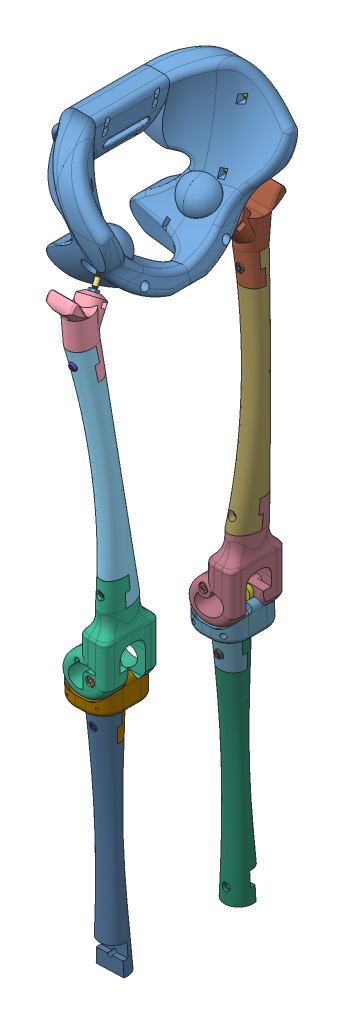
SolidWorks assembly 10_AH_001, configuration Default. Lengths in mm.
Overall size (197.88 962.11 294.61).
76 component instances, 21 part files, 131 mates.
Components (placement in the parent):
- 09_BA_001-1: 09_BA_001 [Default] at origin size (197.88 962.11 294.61) (flexible)
  - 02_01_PE_001-1: 02_01_PE_001 [Default] at origin size (197.88 220.17 282.18)
  - 6630T310_METRIC BLACK POLYPROPYLENE BALL KNOB-1: 6630T310_METRIC BLACK POLYPROPYLENE BALL KNOB [6630T31] at (-58.671 -58.8069 72.4936) x (0.804974 0.48308 0.344458) z (-0.194905 0.763657 -0.6155) size (38 38 37.9)
  - 92997A108_CORROSION-RESISTANT SETUP STUD-1: 92997A108_CORROSION-RESISTANT SETUP STUD [92997A108] at (-55.0653 -72.9345 83.8804) x (0.017759 0.630179 0.776247) z (0.194905 -0.763657 0.6155) size (6.34 6.15 50.8)
  - 03_02_FH_R_001-1: 03_02_FH_R_001 [Default] at (-45.3395 -121.5667 106.123) x (1 0 0) z (0 -0.087156 0.996195) size (46.92 105.86 63.35)
  - 03_01_FB_R_001-1: 03_01_FB_R_001 [Default] at (-44.1058 -425.8587 87.0078) x (1 0 0) z (0 -0.087156 0.996195) size (54.81 304.92 50.87)
  - 04_01_KT_R_001-1: 04_01_KT_R_001 [Default] at (-35.6321 -504.5163 84.7583) size (77.01 157.24 74.14)
  - 04_05_BL_001-1: 04_05_BL_001 [Default] at (-42.5577 -521.5571 84.8583) x (0.712112 0.702066 0) z (0 0 1) size (62.75 16 5.9)
  - 04_06_FL_001-1: 04_06_FL_001 [Default] at (-31.6099 -512.6089 78.7583) x (0.469804 -0.882771 0) z (0 0 1) size (67.43 16 5.9)
  - 04_02_KB_R_001-1: 04_02_KB_R_001 [Default] at (-43.0474 -546.2764 84.7583) x (0.999391 0.034899 0) z (0 0 1) size (78.49 85.12 75.75)
  - 05_01_TI_R_001-1: 05_01_TI_R_001 [Default] at (-42.6984 -556.2703 84.7583) x (0.999391 0.034899 0) z (0 0 1) size (38.19 304.9 38.19)
  - 6630T310_METRIC BLACK POLYPROPYLENE BALL KNOB-2: 6630T310_METRIC BLACK POLYPROPYLENE BALL KNOB [6630T31] at (-58.671 -58.8069 -72.4936) x (0.963134 0.030376 0.2673) z (-0.194905 0.763657 0.6155) size (38 38 37.9)
  - 92997A108_CORROSION-RESISTANT SETUP STUD-2: 92997A108_CORROSION-RESISTANT SETUP STUD [92997A108] at (-55.0653 -72.9345 -83.8804) x (-0.54916 -0.604916 0.576628) z (-0.194905 0.763657 0.6155) size (6.34 6.15 50.8)
  - 03_04_FH_L_001-1: 03_04_FH_L_001 [Default] at (-45.3395 -121.5667 -106.123) x (1 0 0) z (0 0.087156 0.996195) size (46.92 105.86 63.35)
  - 03_03_FB_L_001-1: 03_03_FB_L_001 [Default] at (-44.1058 -425.8587 -87.0078) x (1 0 0) z (0 0.087156 0.996195) size (54.81 304.92 50.87)
  - 04_03_KT_L_001-1: 04_03_KT_L_001 [Default] at (-35.6321 -504.5163 -84.7583) size (77.01 157.24 74.14)
  - 04_05_BL_001-2: 04_05_BL_001 [Default] at (-42.5577 -521.5571 -90.7583) x (0.712112 0.702066 0) z (0 0 1) size (62.75 16 5.9)
  - 04_06_FL_001-2: 04_06_FL_001 [Default] at (-31.6099 -512.6089 -84.6583) x (-0.469804 0.882771 0) z (0 0 1) size (67.43 16 5.9)
  - 04_04_KB_L_001-1: 04_04_KB_L_001 [Default] at (-43.0474 -546.2764 -84.8583) x (0.999391 0.034899 0) z (0 0 1) size (78.49 85.12 75.75)
  - 05_02_TI_001-1: 05_02_TI_001 [Default] at (-42.6984 -556.2703 -84.8583) x (0.999391 0.034899 0) z (0 0 1) size (38.19 304.9 38.19)
- 94645A205_HIGH-STRENGTH STEEL NYLON-INSERT LOCKNUT-1: 94645A205_HIGH-STRENGTH STEEL NYLON-INSERT LOCKNUT [94645A205] at (-47.544 52.8275 110.8479) x (0 -1 0) z (0 0 1) size (10 6.41 11.55)
- 94645A205_HIGH-STRENGTH STEEL NYLON-INSERT LOCKNUT-2: 94645A205_HIGH-STRENGTH STEEL NYLON-INSERT LOCKNUT [94645A205] at (-47.544 -21.0136 84.8541) x (0 -1 0) z (0 0 1) size (10 6.41 11.55)
- 94645A205_HIGH-STRENGTH STEEL NYLON-INSERT LOCKNUT-4: 94645A205_HIGH-STRENGTH STEEL NYLON-INSERT LOCKNUT [94645A205] at (-74.544 -75.4386 54.7323) x (0 1 0) z (0 0 1) size (10 6.41 11.55)
- 94645A205_HIGH-STRENGTH STEEL NYLON-INSERT LOCKNUT-6: 94645A205_HIGH-STRENGTH STEEL NYLON-INSERT LOCKNUT [94645A205] at (-47.544 52.8275 -110.8479) x (0 1 0) z (0 0 -1) size (10 6.41 11.55)
- 94645A205_HIGH-STRENGTH STEEL NYLON-INSERT LOCKNUT-8: 94645A205_HIGH-STRENGTH STEEL NYLON-INSERT LOCKNUT [94645A205] at (-47.544 -21.0136 -84.8541) x (0 1 0) z (0 0 -1) size (10 6.41 11.55)
- 94645A205_HIGH-STRENGTH STEEL NYLON-INSERT LOCKNUT-10: 94645A205_HIGH-STRENGTH STEEL NYLON-INSERT LOCKNUT [94645A205] at (-74.544 -75.4386 -54.7323) x (0 1 0) z (0 0 1) size (10 6.41 11.55)
- 94645A205_HIGH-STRENGTH STEEL NYLON-INSERT LOCKNUT-12: 94645A205_HIGH-STRENGTH STEEL NYLON-INSERT LOCKNUT [94645A205] at (-104.3146 69.6752 36.5) x (0 1 0) z (-1 0 0) size (10 6.41 11.55)
- 94645A205_HIGH-STRENGTH STEEL NYLON-INSERT LOCKNUT-14: 94645A205_HIGH-STRENGTH STEEL NYLON-INSERT LOCKNUT [94645A205] at (-121.884 56.6312 36.5) x (0 1 0) z (-1 0 0) size (10 6.41 11.55)
- 94645A205_HIGH-STRENGTH STEEL NYLON-INSERT LOCKNUT-16: 94645A205_HIGH-STRENGTH STEEL NYLON-INSERT LOCKNUT [94645A205] at (-121.884 56.6312 -30.5) x (0 1 0) z (-1 0 0) size (10 6.41 11.55)
- 94645A205_HIGH-STRENGTH STEEL NYLON-INSERT LOCKNUT-18: 94645A205_HIGH-STRENGTH STEEL NYLON-INSERT LOCKNUT [94645A205] at (-104.3146 69.6752 -30.5) x (0 1 0) z (-1 0 0) size (10 6.41 11.55)
- 94645A205_HIGH-STRENGTH STEEL NYLON-INSERT LOCKNUT-20: 94645A205_HIGH-STRENGTH STEEL NYLON-INSERT LOCKNUT [94645A205] at (-51.8494 -85.5349 94.0361) x (0.194905 0.645175 0.738757) z (0.961262 0.024023 -0.274588) size (10 6.41 11.55)
- 94645A205_HIGH-STRENGTH STEEL NYLON-INSERT LOCKNUT-22: 94645A205_HIGH-STRENGTH STEEL NYLON-INSERT LOCKNUT [94645A205] at (-51.8494 -85.5349 -94.0361) x (0.194905 0.645175 -0.738757) z (-0.961262 -0.024023 -0.274588) size (10 6.41 11.55)
- 94645A205_HIGH-STRENGTH STEEL NYLON-INSERT LOCKNUT-24: 94645A205_HIGH-STRENGTH STEEL NYLON-INSERT LOCKNUT [94645A205] at (-30.2115 -92.3012 -13.5) x (0.866025 -0.5 0) z (0.5 0.866025 0) size (10 6.41 11.55)
- 94645A205_HIGH-STRENGTH STEEL NYLON-INSERT LOCKNUT-26: 94645A205_HIGH-STRENGTH STEEL NYLON-INSERT LOCKNUT [94645A205] at (-41.8015 -140.2036 100.5688) x (0.866025 -0.498097 -0.043578) z (0.5 0.86273 0.075479) size (10 6.41 11.55)
- 94645A205_HIGH-STRENGTH STEEL NYLON-INSERT LOCKNUT-28: 94645A205_HIGH-STRENGTH STEEL NYLON-INSERT LOCKNUT [94645A205] at (-41.8015 -140.2036 -100.5688) x (0.866025 -0.498097 0.043578) z (-0.5 -0.86273 0.075479) size (10 6.41 11.55)
- 94645A205_HIGH-STRENGTH STEEL NYLON-INSERT LOCKNUT-30: 94645A205_HIGH-STRENGTH STEEL NYLON-INSERT LOCKNUT [94645A205] at (-23.6321 -408.0461 -101.9838) x (1 0 0) z (0 0.996195 -0.087156) size (10 6.41 11.55)
- 94645A205_HIGH-STRENGTH STEEL NYLON-INSERT LOCKNUT-36: 94645A205_HIGH-STRENGTH STEEL NYLON-INSERT LOCKNUT [94645A205] at (-41.8513 -575.3023 71.7583) x (0.999391 0.034899 0) z (-0.034899 0.999391 0) size (10 6.41 11.55)
- 94645A205_HIGH-STRENGTH STEEL NYLON-INSERT LOCKNUT-39: 94645A205_HIGH-STRENGTH STEEL NYLON-INSERT LOCKNUT [94645A205] at (-23.6321 -408.0461 101.9838) x (-0.5 0.86273 0.075479) z (0.866025 0.498097 0.043578) size (10 6.41 11.55)
- 94645A205_HIGH-STRENGTH STEEL NYLON-INSERT LOCKNUT-41: 94645A205_HIGH-STRENGTH STEEL NYLON-INSERT LOCKNUT [94645A205] at (-41.8513 -575.3023 -71.8583) x (0.999391 0.034899 0) z (0.034899 -0.999391 0) size (10 6.41 11.55)
- 91239A330_CLASS 10.9 STL BUTTON-HEAD SOCKET CAP SCREW-1: 91239A330_CLASS 10.9 STL BUTTON-HEAD SOCKET CAP SCREW [91239A330] at (-121.884 56.6312 66.8) size (10.5 10.5 38.95)
- 91239A330_CLASS 10.9 STL BUTTON-HEAD SOCKET CAP SCREW-2: 91239A330_CLASS 10.9 STL BUTTON-HEAD SOCKET CAP SCREW [91239A330] at (-77.844 52.8275 110.8479) x (0 0 1) z (-1 0 0) size (10.5 10.5 38.95)
- 91239A330_CLASS 10.9 STL BUTTON-HEAD SOCKET CAP SCREW-4: 91239A330_CLASS 10.9 STL BUTTON-HEAD SOCKET CAP SCREW [91239A330] at (-104.3146 69.6752 66.8) x (0.959125 0.282984 0) z (0 0 1) size (10.5 10.5 38.95)
- 91239A330_CLASS 10.9 STL BUTTON-HEAD SOCKET CAP SCREW-6: 91239A330_CLASS 10.9 STL BUTTON-HEAD SOCKET CAP SCREW [91239A330] at (-104.3146 69.6752 -66.8) x (-0.5 0.866025 0) z (0 0 -1) size (10.5 10.5 38.95)
- 91239A330_CLASS 10.9 STL BUTTON-HEAD SOCKET CAP SCREW-8: 91239A330_CLASS 10.9 STL BUTTON-HEAD SOCKET CAP SCREW [91239A330] at (-121.884 56.6312 -66.8) x (-0.642788 0.766044 0) z (0 0 -1) size (10.5 10.5 38.95)
- 91239A330_CLASS 10.9 STL BUTTON-HEAD SOCKET CAP SCREW-10: 91239A330_CLASS 10.9 STL BUTTON-HEAD SOCKET CAP SCREW [91239A330] at (-77.844 52.8275 -110.8479) x (0 0 1) z (-1 0 0) size (10.5 10.5 38.95)
- 91239A330_CLASS 10.9 STL BUTTON-HEAD SOCKET CAP SCREW-12: 91239A330_CLASS 10.9 STL BUTTON-HEAD SOCKET CAP SCREW [91239A330] at (-77.844 -21.0136 -84.8541) x (0 0 1) z (-1 0 0) size (10.5 10.5 38.95)
- 91239A330_CLASS 10.9 STL BUTTON-HEAD SOCKET CAP SCREW-14: 91239A330_CLASS 10.9 STL BUTTON-HEAD SOCKET CAP SCREW [91239A330] at (-77.844 -21.0136 84.8541) x (0 0 1) z (-1 0 0) size (10.5 10.5 38.95)
- 91239A330_CLASS 10.9 STL BUTTON-HEAD SOCKET CAP SCREW-16: 91239A330_CLASS 10.9 STL BUTTON-HEAD SOCKET CAP SCREW [91239A330] at (-44.244 -75.4386 -54.7323) x (0 0.171049 -0.985262) z (1 0 0) size (10.5 10.5 38.95)
- 91239A330_CLASS 10.9 STL BUTTON-HEAD SOCKET CAP SCREW-18: 91239A330_CLASS 10.9 STL BUTTON-HEAD SOCKET CAP SCREW [91239A330] at (-44.244 -75.4386 54.7323) x (0 0 -1) z (1 0 0) size (10.5 10.5 38.95)
- 91239A330_CLASS 10.9 STL BUTTON-HEAD SOCKET CAP SCREW-20: 91239A330_CLASS 10.9 STL BUTTON-HEAD SOCKET CAP SCREW [91239A330] at (-30.2115 -92.3012 16.8) x (0.985697 -0.168526 0) z (0 0 1) size (10.5 10.5 38.95)
- 91239A330_CLASS 10.9 STL BUTTON-HEAD SOCKET CAP SCREW-22: 91239A330_CLASS 10.9 STL BUTTON-HEAD SOCKET CAP SCREW [91239A330] at (-41.8015 -142.9042 131.4369) x (0.92579 -0.376599 -0.032948) z (0 -0.087156 0.996195) size (10.5 10.5 38.95)
- 91239A330_CLASS 10.9 STL BUTTON-HEAD SOCKET CAP SCREW-24: 91239A330_CLASS 10.9 STL BUTTON-HEAD SOCKET CAP SCREW [91239A330] at (-41.8015 -142.9042 -131.4369) x (-0.916799 -0.39783 0.034806) z (0 -0.087156 -0.996195) size (10.5 10.5 38.95)
- 91239A330_CLASS 10.9 STL BUTTON-HEAD SOCKET CAP SCREW-26: 91239A330_CLASS 10.9 STL BUTTON-HEAD SOCKET CAP SCREW [91239A330] at (-23.6321 -405.415 -71.9097) x (0.92535 -0.377672 0.033042) z (0 0.087156 0.996195) size (10.5 10.5 38.95)
- 91239A330_CLASS 10.9 STL BUTTON-HEAD SOCKET CAP SCREW-28: 91239A330_CLASS 10.9 STL BUTTON-HEAD SOCKET CAP SCREW [91239A330] at (-23.6321 -405.415 71.9097) x (-0.509415 -0.857247 -0.074999) z (0 0.087156 -0.996195) size (10.5 10.5 38.95)
- 91239A330_CLASS 10.9 STL BUTTON-HEAD SOCKET CAP SCREW-30: 91239A330_CLASS 10.9 STL BUTTON-HEAD SOCKET CAP SCREW [91239A330] at (-41.8513 -575.3023 -102.1583) x (-0.5 -0.866025 0) z (0 0 -1) size (10.5 10.5 38.95)
- 91239A330_CLASS 10.9 STL BUTTON-HEAD SOCKET CAP SCREW-32: 91239A330_CLASS 10.9 STL BUTTON-HEAD SOCKET CAP SCREW [91239A330] at (-41.8513 -575.3023 102.0583) x (-0.675882 0.73701 0) z (0 0 1) size (10.5 10.5 38.95)
- 91595A476_METRIC ALLOY STEEL DOWEL PIN-1: 91595A476_METRIC ALLOY STEEL DOWEL PIN [91595A476] at (-59.6817 24.9417 100.1676) x (1 0 0) z (0 0.020434 0.999791) size (40 6 6)
- 91595A476_METRIC ALLOY STEEL DOWEL PIN-2: 91595A476_METRIC ALLOY STEEL DOWEL PIN [91595A476] at (-59.6817 -3.0834 90.0569) x (1 0 0) z (0 -0.138344 0.990384) size (40 6 6)
- 91595A476_METRIC ALLOY STEEL DOWEL PIN-4: 91595A476_METRIC ALLOY STEEL DOWEL PIN [91595A476] at (-59.6817 -93.1682 40.0283) x (1 0 0) z (0 -0.263326 0.964707) size (40 6 6)
- 91595A476_METRIC ALLOY STEEL DOWEL PIN-6: 91595A476_METRIC ALLOY STEEL DOWEL PIN [91595A476] at (-59.6817 -93.1682 -40.0283) x (1 0 0) z (0 -0.780184 0.62555) size (40 6 6)
- 91595A476_METRIC ALLOY STEEL DOWEL PIN-8: 91595A476_METRIC ALLOY STEEL DOWEL PIN [91595A476] at (-62.6563 -3.0834 -90.0569) x (-1 0 0) z (0 0.779019 -0.627) size (40 6 6)
- 91595A476_METRIC ALLOY STEEL DOWEL PIN-10: 91595A476_METRIC ALLOY STEEL DOWEL PIN [91595A476] at (-59.6817 24.9417 -100.1676) x (1 0 0) z (0 -0.947084 0.320986) size (40 6 6)
- 90695A038_CLASS 04 STEEL THIN HEX NUT - DIN 439B-1: 90695A038_CLASS 04 STEEL THIN HEX NUT - DIN 439B [90695A038] at (-53.3306 -79.7311 89.3583) x (0.978461 0.194905 -0.06802) z (-0.06802 0.6155 0.785196) size (10 3.98 11.55)
- 90695A038_CLASS 04 STEEL THIN HEX NUT - DIN 439B-2: 90695A038_CLASS 04 STEEL THIN HEX NUT - DIN 439B [90695A038] at (-53.3306 -79.7311 -89.3583) x (0.826706 -0.20978 0.522062) z (-0.527796 -0.61059 0.590433) size (10 3.98 11.55)
- 94510A255_BRASS SCREW-TO-EXPAND INSERTS-1: 94510A255_BRASS SCREW-TO-EXPAND INSERTS [94510A255] at (-25.9121 -505.1463 120.7537) x (1 0 0) z (0 -1 0) size (9.53 13.25 9.53)
- 94510A255_BRASS SCREW-TO-EXPAND INSERTS-2: 94510A255_BRASS SCREW-TO-EXPAND INSERTS [94510A255] at (-25.9121 -505.1463 -120.7537) x (0.972777 0.231744 0) z (-0.231744 0.972777 0) size (9.53 13.25 9.53)
- 94510A255_BRASS SCREW-TO-EXPAND INSERTS-4: 94510A255_BRASS SCREW-TO-EXPAND INSERTS [94510A255] at (-43.6921 -489.9063 48.7629) x (-0.34202 0.939693 0) z (-0.939693 -0.34202 0) size (9.53 13.25 9.53)
- 94510A255_BRASS SCREW-TO-EXPAND INSERTS-6: 94510A255_BRASS SCREW-TO-EXPAND INSERTS [94510A255] at (-43.6921 -489.9063 -48.7629) x (-0.130134 -0.991496 0) z (-0.991496 0.130134 0) size (9.53 13.25 9.53)
- 97493A126_ METRIC PARTIALLY THREADED STUDS-1: 97493A126_ METRIC PARTIALLY THREADED STUDS [97493A126] at (-25.9121 -505.1463 -107.6583) x (-0.1 0.994987 0) z (0 0 1) size (6.22 6.14 30.07)
- 97493A126_ METRIC PARTIALLY THREADED STUDS-2: 97493A126_ METRIC PARTIALLY THREADED STUDS [97493A126] at (-43.6921 -489.9063 -61.8583) x (0.997236 0.074297 0) z (0 0 -1) size (6.22 6.14 30.07)
- 97493A126_ METRIC PARTIALLY THREADED STUDS-4: 97493A126_ METRIC PARTIALLY THREADED STUDS [97493A126] at (-43.6921 -489.9063 61.8583) x (0.989622 0.143697 0) z (0 0 1) size (6.22 6.14 30.07)
- 97493A126_ METRIC PARTIALLY THREADED STUDS-6: 97493A126_ METRIC PARTIALLY THREADED STUDS [97493A126] at (-25.9121 -505.1463 107.6583) x (0.911684 0.410891 0) z (0 0 -1) size (6.22 6.14 30.07)
- 97493A126_ METRIC PARTIALLY THREADED STUDS-9: 97493A126_ METRIC PARTIALLY THREADED STUDS [97493A126] at (-19.5277 -535.3116 92.5583) x (-1 0 0) z (0 0 -1) size (6.22 6.14 30.07)
- 97493A126_ METRIC PARTIALLY THREADED STUDS-10: 97493A126_ METRIC PARTIALLY THREADED STUDS [97493A126] at (-59.2033 -537.9679 92.5583) x (-0.987351 -0.158553 0) z (0 0 -1) size (6.22 6.14 30.07)
- 97493A126_ METRIC PARTIALLY THREADED STUDS-12: 97493A126_ METRIC PARTIALLY THREADED STUDS [97493A126] at (-19.5277 -535.3116 -92.6583) x (-0.994367 -0.105992 0) z (0 0 1) size (6.22 6.14 30.07)
- 97493A126_ METRIC PARTIALLY THREADED STUDS-14: 97493A126_ METRIC PARTIALLY THREADED STUDS [97493A126] at (-59.2033 -537.9679 -92.6583) x (-0.999918 -0.012843 0) z (0 0 1) size (6.22 6.14 30.07)
Mates (geometry in assembly coordinates):
- Coincident1: coincident anti-aligned: plane of 09_BipedalRobot_Assembly-1/02_01_Pelvis-1 through (-47.544 0 0) normal (1 0 0); plane of 94645A205_HIGH-STRENGTH STEEL NYLON-INSERT LOCKNUT-1 through (-47.544 47.8275 107.9612) normal (-1 0 0)
- Parallel1: parallel anti-aligned: plane of 09_BipedalRobot_Assembly-1/02_01_Pelvis-1 through (-41.044 57.9775 107.8746) normal (0 -1 0); plane of 94645A205_HIGH-STRENGTH STEEL NYLON-INSERT LOCKNUT-1 through (-41.544 57.8275 107.9612) normal (0 1 0)
- Concentric4: concentric anti-aligned: circle of 09_BipedalRobot_Assembly-1/02_01_Pelvis-1; circle of 94645A205_HIGH-STRENGTH STEEL NYLON-INSERT LOCKNUT-1
- Coincident3: coincident anti-aligned: plane of 09_BipedalRobot_Assembly-1/02_01_Pelvis-1 through (-47.544 0 0) normal (1 0 0); plane of 94645A205_HIGH-STRENGTH STEEL NYLON-INSERT LOCKNUT-2 through (-47.544 -26.0136 81.9674) normal (-1 0 0)
- Parallel2: parallel anti-aligned: plane of 09_BipedalRobot_Assembly-1/02_01_Pelvis-1 through (-41.044 -15.8636 81.8808) normal (0 -1 0); plane of 94645A205_HIGH-STRENGTH STEEL NYLON-INSERT LOCKNUT-2 through (-41.544 -16.0136 81.9674) normal (0 1 0)
- Concentric5: concentric anti-aligned: circle of 09_BipedalRobot_Assembly-1/02_01_Pelvis-1; circle of 94645A205_HIGH-STRENGTH STEEL NYLON-INSERT LOCKNUT-2
- Parallel3: parallel anti-aligned: plane of 09_BipedalRobot_Assembly-1/02_01_Pelvis-1 through (-81.044 -80.5886 57.7056) normal (0 1 0); plane of 94645A205_HIGH-STRENGTH STEEL NYLON-INSERT LOCKNUT-4 through (-80.544 -80.4386 51.8455) normal (0 -1 0)
- Concentric6: concentric anti-aligned: circle of 09_BipedalRobot_Assembly-1/02_01_Pelvis-1; circle of 94645A205_HIGH-STRENGTH STEEL NYLON-INSERT LOCKNUT-4
- Coincident5: coincident anti-aligned: plane of 09_BipedalRobot_Assembly-1/02_01_Pelvis-1 through (-74.544 0 0) normal (-1 0 0); plane of 94645A205_HIGH-STRENGTH STEEL NYLON-INSERT LOCKNUT-4 through (-74.544 -70.4386 51.8455) normal (1 0 0)
- Coincident6: coincident anti-aligned: plane of 09_BipedalRobot_Assembly-1/02_01_Pelvis-1 through (-47.544 0 0) normal (1 0 0); plane of 94645A205_HIGH-STRENGTH STEEL NYLON-INSERT LOCKNUT-6 through (-47.544 57.8275 -107.9612) normal (-1 0 0)
- Parallel4: parallel anti-aligned: plane of 09_BipedalRobot_Assembly-1/02_01_Pelvis-1 through (-41.044 47.6775 -113.8213) normal (0 1 0); plane of 94645A205_HIGH-STRENGTH STEEL NYLON-INSERT LOCKNUT-6 through (-41.544 47.8275 -107.9612) normal (0 -1 0)
- Concentric7: concentric aligned: circle of 09_BipedalRobot_Assembly-1/02_01_Pelvis-1; circle of 94645A205_HIGH-STRENGTH STEEL NYLON-INSERT LOCKNUT-6
- Coincident7: coincident anti-aligned: plane of 09_BipedalRobot_Assembly-1/02_01_Pelvis-1 through (-47.544 0 0) normal (1 0 0); plane of 94645A205_HIGH-STRENGTH STEEL NYLON-INSERT LOCKNUT-8 through (-47.544 -16.0136 -81.9674) normal (-1 0 0)
- Parallel5: parallel anti-aligned: plane of 09_BipedalRobot_Assembly-1/02_01_Pelvis-1 through (-41.044 -26.1636 -87.8275) normal (0 1 0); plane of 94645A205_HIGH-STRENGTH STEEL NYLON-INSERT LOCKNUT-8 through (-41.544 -26.0136 -81.9674) normal (0 -1 0)
- Concentric8: concentric aligned: circle of 09_BipedalRobot_Assembly-1/02_01_Pelvis-1; circle of 94645A205_HIGH-STRENGTH STEEL NYLON-INSERT LOCKNUT-8
- Coincident8: coincident anti-aligned: plane of 09_BipedalRobot_Assembly-1/02_01_Pelvis-1 through (-74.544 0 0) normal (-1 0 0); plane of 94645A205_HIGH-STRENGTH STEEL NYLON-INSERT LOCKNUT-10 through (-74.544 -70.4386 -57.619) normal (1 0 0)
- Parallel6: parallel anti-aligned: plane of 09_BipedalRobot_Assembly-1/02_01_Pelvis-1 through (-81.044 -80.5886 -57.7056) normal (0 1 0); plane of 94645A205_HIGH-STRENGTH STEEL NYLON-INSERT LOCKNUT-10 through (-80.544 -80.4386 -57.619) normal (0 -1 0)
- Concentric11: concentric aligned: circle of 09_BipedalRobot_Assembly-1/02_01_Pelvis-1; circle of 94645A205_HIGH-STRENGTH STEEL NYLON-INSERT LOCKNUT-10
- Coincident9: coincident anti-aligned: plane of 09_BipedalRobot_Assembly-1/02_01_Pelvis-1 through (0 0 36.5) normal (0 0 -1); plane of 94645A205_HIGH-STRENGTH STEEL NYLON-INSERT LOCKNUT-12 through (-101.4278 74.6752 36.5) normal (0 0 1)
- Parallel7: parallel anti-aligned: plane of 09_BipedalRobot_Assembly-1/02_01_Pelvis-1 through (-101.3412 64.5252 30.5) normal (0 1 0); plane of 94645A205_HIGH-STRENGTH STEEL NYLON-INSERT LOCKNUT-12 through (-101.4278 64.6752 30.5) normal (0 -1 0)
- Concentric12: concentric anti-aligned: circle of 09_BipedalRobot_Assembly-1/02_01_Pelvis-1; circle of 94645A205_HIGH-STRENGTH STEEL NYLON-INSERT LOCKNUT-12
- Coincident10: coincident anti-aligned: plane of 09_BipedalRobot_Assembly-1/02_01_Pelvis-1 through (0 0 36.5) normal (0 0 -1); plane of 94645A205_HIGH-STRENGTH STEEL NYLON-INSERT LOCKNUT-14 through (-118.9973 61.6312 36.5) normal (0 0 1)
- Parallel8: parallel anti-aligned: plane of 09_BipedalRobot_Assembly-1/02_01_Pelvis-1 through (-118.9107 51.4812 30.5) normal (0 1 0); plane of 94645A205_HIGH-STRENGTH STEEL NYLON-INSERT LOCKNUT-14 through (-118.9973 51.6312 30.5) normal (0 -1 0)
- Concentric13: concentric anti-aligned: circle of 09_BipedalRobot_Assembly-1/02_01_Pelvis-1; circle of 94645A205_HIGH-STRENGTH STEEL NYLON-INSERT LOCKNUT-14
- Coincident11: coincident anti-aligned: plane of 09_BipedalRobot_Assembly-1/02_01_Pelvis-1 through (0 0 -30.5) normal (0 0 -1); plane of 94645A205_HIGH-STRENGTH STEEL NYLON-INSERT LOCKNUT-16 through (-118.9973 61.6312 -30.5) normal (0 0 1)
- Parallel9: parallel anti-aligned: plane of 09_BipedalRobot_Assembly-1/02_01_Pelvis-1 through (-118.9107 51.4812 -30.5) normal (0 1 0); plane of 94645A205_HIGH-STRENGTH STEEL NYLON-INSERT LOCKNUT-16 through (-118.9973 51.6312 -36.5) normal (0 -1 0)
- Concentric14: concentric anti-aligned: circle of 09_BipedalRobot_Assembly-1/02_01_Pelvis-1; circle of 94645A205_HIGH-STRENGTH STEEL NYLON-INSERT LOCKNUT-16
- Coincident12: coincident anti-aligned: plane of 09_BipedalRobot_Assembly-1/02_01_Pelvis-1 through (0 0 -30.5) normal (0 0 -1); plane of 94645A205_HIGH-STRENGTH STEEL NYLON-INSERT LOCKNUT-18 through (-101.4278 74.6752 -30.5) normal (0 0 1)
- Parallel10: parallel anti-aligned: plane of 09_BipedalRobot_Assembly-1/02_01_Pelvis-1 through (-101.3412 64.5252 -30.5) normal (0 1 0); plane of 94645A205_HIGH-STRENGTH STEEL NYLON-INSERT LOCKNUT-18 through (-101.4278 64.6752 -36.5) normal (0 -1 0)
- Concentric15: concentric anti-aligned: circle of 09_BipedalRobot_Assembly-1/02_01_Pelvis-1; circle of 94645A205_HIGH-STRENGTH STEEL NYLON-INSERT LOCKNUT-18
- Coincident13: coincident anti-aligned: plane of 09_BipedalRobot_Assembly-1/03_02_FemurHead_Right-1 through (-53.3962 -90.6553 88.173) normal (0.194905 -0.763657 0.6155); plane of 94645A205_HIGH-STRENGTH STEEL NYLON-INSERT LOCKNUT-20 through (-53.6498 -82.3783 98.5226) normal (-0.194905 0.763657 -0.6155)
- Parallel11: parallel anti-aligned: plane of 09_BipedalRobot_Assembly-1/03_02_FemurHead_Right-1 through (-19.7212 -93.0069 85.1522) normal (0.194905 0.645175 0.738757); plane of 94645A205_HIGH-STRENGTH STEEL NYLON-INSERT LOCKNUT-20 through (-54.4294 -93.412 94.828) normal (-0.194905 -0.645175 -0.738757)
- Concentric16: concentric aligned: circle of 09_BipedalRobot_Assembly-1/03_02_FemurHead_Right-1; circle of 94645A205_HIGH-STRENGTH STEEL NYLON-INSERT LOCKNUT-20
- Coincident14: coincident anti-aligned: plane of 09_BipedalRobot_Assembly-1/03_04_FemurHead_Left-1 through (-53.3962 -90.6553 -88.173) normal (0.194905 -0.763657 -0.6155); plane of 94645A205_HIGH-STRENGTH STEEL NYLON-INSERT LOCKNUT-22 through (-48.0999 -82.2396 -96.9372) normal (-0.194905 0.763657 0.6155)
- Parallel12: parallel anti-aligned: plane of 09_BipedalRobot_Assembly-1/03_04_FemurHead_Left-1 through (-19.7212 -93.0069 -85.1522) normal (0.194905 0.645175 -0.738757); plane of 94645A205_HIGH-STRENGTH STEEL NYLON-INSERT LOCKNUT-22 through (-48.8795 -93.2733 -93.2427) normal (-0.194905 -0.645175 0.738757)
- Concentric17: concentric anti-aligned: circle of 09_BipedalRobot_Assembly-1/03_04_FemurHead_Left-1; circle of 94645A205_HIGH-STRENGTH STEEL NYLON-INSERT LOCKNUT-22
- Coincident15: coincident anti-aligned: plane of 09_BipedalRobot_Assembly-1/02_01_Pelvis-1 through (0 0 -13.5) normal (0 0 -1); plane of 94645A205_HIGH-STRENGTH STEEL NYLON-INSERT LOCKNUT-24 through (-27.3247 -97.3012 -13.5) normal (0 0 1)
- Parallel13: parallel anti-aligned: plane of 09_BipedalRobot_Assembly-1/02_01_Pelvis-1 through (-36.1582 -92.3012 -143.5354) normal (0.866025 -0.5 0); plane of 94645A205_HIGH-STRENGTH STEEL NYLON-INSERT LOCKNUT-24 through (-35.985 -92.3012 -19.5) normal (-0.866025 0.5 0)
- Concentric18: concentric aligned: circle of 09_BipedalRobot_Assembly-1/02_01_Pelvis-1; circle of 94645A205_HIGH-STRENGTH STEEL NYLON-INSERT LOCKNUT-24
- Coincident16: coincident anti-aligned: plane of 09_BipedalRobot_Assembly-1/03_02_FemurHead_Right-1 through (-45.3395 -121.2261 102.2291) normal (0 0.087156 -0.996195); plane of 94645A205_HIGH-STRENGTH STEEL NYLON-INSERT LOCKNUT-26 through (-38.9147 -145.1846 100.133) normal (0 -0.087156 0.996195)
- Parallel14: parallel anti-aligned: plane of 09_BipedalRobot_Assembly-1/03_02_FemurHead_Right-1 through (-47.8637 -139.5343 92.9194) normal (0.866025 -0.498097 -0.043578); plane of 94645A205_HIGH-STRENGTH STEEL NYLON-INSERT LOCKNUT-26 through (-47.575 -139.6806 94.5917) normal (-0.866025 0.498097 0.043578)
- Concentric19: concentric aligned: circle of 09_BipedalRobot_Assembly-1/03_02_FemurHead_Right-1; circle of 94645A205_HIGH-STRENGTH STEEL NYLON-INSERT LOCKNUT-26
- Coincident17: coincident anti-aligned: plane of 09_BipedalRobot_Assembly-1/03_04_FemurHead_Left-1 through (-45.3395 -121.2261 -102.2291) normal (0 0.087156 0.996195); plane of 94645A205_HIGH-STRENGTH STEEL NYLON-INSERT LOCKNUT-28 through (-36.028 -140.2036 -100.5688) normal (0 -0.087156 -0.996195)
- Parallel15: parallel anti-aligned: plane of 09_BipedalRobot_Assembly-1/03_04_FemurHead_Left-1 through (-47.8637 -139.5343 -92.9194) normal (0.866025 -0.498097 0.043578); plane of 94645A205_HIGH-STRENGTH STEEL NYLON-INSERT LOCKNUT-28 through (-44.6882 -134.6997 -95.0274) normal (-0.866025 0.498097 -0.043578)
- Concentric20: concentric anti-aligned: circle of 09_BipedalRobot_Assembly-1/03_04_FemurHead_Left-1; circle of 94645A205_HIGH-STRENGTH STEEL NYLON-INSERT LOCKNUT-28
- Coincident18: coincident anti-aligned: plane of 09_BipedalRobot_Assembly-1/04_03_KneeTop_Left-1 through (-35.6321 -505.2791 -93.4771) normal (0 -0.087156 -0.996195); plane of 94645A205_HIGH-STRENGTH STEEL NYLON-INSERT LOCKNUT-30 through (-18.6321 -410.9219 -101.7322) normal (0 0.087156 0.996195)
- Parallel16: parallel anti-aligned: plane of 09_BipedalRobot_Assembly-1/04_03_KneeTop_Left-1 through (-28.8821 -407.1183 -126.1567) normal (1 0 0); plane of 94645A205_HIGH-STRENGTH STEEL NYLON-INSERT LOCKNUT-30 through (-28.6321 -411.4448 -107.7094) normal (-1 0 0)
- Concentric21: concentric anti-aligned: circle of 09_BipedalRobot_Assembly-1/04_03_KneeTop_Left-1; circle of 94645A205_HIGH-STRENGTH STEEL NYLON-INSERT LOCKNUT-30
- Coincident21: coincident anti-aligned: plane of 09_BipedalRobot_Assembly-1/04_02_KneeBottom_Right-1 through (-43.0474 -546.2764 71.7583) normal (0 0 -1); plane of 94645A205_HIGH-STRENGTH STEEL NYLON-INSERT LOCKNUT-36 through (-36.7536 -578.0128 71.7583) normal (0 0 1)
- Parallel19: parallel anti-aligned: plane of 09_BipedalRobot_Assembly-1/04_02_KneeBottom_Right-1 through (-47.2039 -572.4563 46.8849) normal (0.999391 0.034899 0); plane of 94645A205_HIGH-STRENGTH STEEL NYLON-INSERT LOCKNUT-36 through (-46.7476 -578.3618 65.7583) normal (-0.999391 -0.034899 0)
- Concentric24: concentric anti-aligned: circle of 09_BipedalRobot_Assembly-1/04_02_KneeBottom_Right-1; circle of 94645A205_HIGH-STRENGTH STEEL NYLON-INSERT LOCKNUT-36
- Coincident23: coincident anti-aligned: plane of 09_BipedalRobot_Assembly-1/04_01_KneeTop_Right-1 through (-35.6321 -505.2791 93.4771) normal (0 -0.087156 0.996195); plane of 94645A205_HIGH-STRENGTH STEEL NYLON-INSERT LOCKNUT-39 through (-28.6321 -405.1704 102.2354) normal (0 0.087156 -0.996195)
- Parallel21: parallel anti-aligned: plane of 09_BipedalRobot_Assembly-1/04_01_KneeTop_Right-1 through (-23.6321 -416.177 125.3642) normal (-0.5 0.86273 0.075479); plane of 94645A205_HIGH-STRENGTH STEEL NYLON-INSERT LOCKNUT-39 through (-23.6321 -414.3206 107.4578) normal (0.5 -0.86273 -0.075479)
- Concentric26: concentric anti-aligned: cylinder of 09_BipedalRobot_Assembly-1/04_01_KneeTop_Right-1 through (-23.6321 -403.1666 46.2101) axis (0 -0.087156 0.996195) radius 3.25; circle of 94645A205_HIGH-STRENGTH STEEL NYLON-INSERT LOCKNUT-39
- Coincident24: coincident anti-aligned: plane of 09_BipedalRobot_Assembly-1/04_04_KneeBottom_Left-1 through (-43.0474 -546.2764 -71.8583) normal (0 0 1); plane of 94645A205_HIGH-STRENGTH STEEL NYLON-INSERT LOCKNUT-41 through (-36.9551 -572.2428 -71.8583) normal (0 0 -1)
- Parallel22: parallel anti-aligned: plane of 09_BipedalRobot_Assembly-1/04_04_KneeBottom_Left-1 through (-47.2039 -572.4563 -46.9849) normal (0.999391 0.034899 0); plane of 94645A205_HIGH-STRENGTH STEEL NYLON-INSERT LOCKNUT-41 through (-46.949 -572.5918 -65.8583) normal (-0.999391 -0.034899 0)
- Concentric27: concentric aligned: cylinder of 09_BipedalRobot_Assembly-1/04_04_KneeBottom_Left-1 through (-41.8513 -575.3023 -46.9849) axis (0 0 -1) radius 3.25; circle of 94645A205_HIGH-STRENGTH STEEL NYLON-INSERT LOCKNUT-41
- Concentric28: concentric aligned: cylinder of 09_BipedalRobot_Assembly-1/02_01_Pelvis-1 through (-121.884 56.6312 143.5354) axis (0 0 -1) radius 5.375; cylinder of 91239A330_CLASS 10.9 STL BUTTON-HEAD SOCKET CAP SCREW-1 through (-121.884 56.6312 28.5) axis (0 0 -1) radius 3
- Coincident25: coincident anti-aligned: plane of 09_BipedalRobot_Assembly-1/02_01_Pelvis-1 through (-121.884 56.6312 63.5) normal (0 0 1); plane of 91239A330_CLASS 10.9 STL BUTTON-HEAD SOCKET CAP SCREW-1 through (-121.884 51.3812 63.5) normal (0 0 -1)
- Concentric29: concentric aligned: cylinder of 09_BipedalRobot_Assembly-1/02_01_Pelvis-1 through (-187.4808 52.8275 110.8479) axis (1 0 0) radius 5.375; cylinder of 91239A330_CLASS 10.9 STL BUTTON-HEAD SOCKET CAP SCREW-2 through (-39.544 52.8275 110.8479) axis (1 0 0) radius 3
- Coincident26: coincident anti-aligned: plane of 09_BipedalRobot_Assembly-1/02_01_Pelvis-1 through (-74.544 52.8275 110.8479) normal (-1 0 0); plane of 91239A330_CLASS 10.9 STL BUTTON-HEAD SOCKET CAP SCREW-2 through (-74.544 47.5775 110.8479) normal (1 0 0)
- Concentric30: concentric aligned: cylinder of 09_BipedalRobot_Assembly-1/02_01_Pelvis-1 through (-104.3146 69.6752 143.5354) axis (0 0 -1) radius 5.375; cylinder of 91239A330_CLASS 10.9 STL BUTTON-HEAD SOCKET CAP SCREW-4 through (-104.3146 69.6752 28.5) axis (0 0 -1) radius 3
- Coincident27: coincident anti-aligned: plane of 09_BipedalRobot_Assembly-1/02_01_Pelvis-1 through (-104.3146 69.6752 63.5) normal (0 0 1); plane of 91239A330_CLASS 10.9 STL BUTTON-HEAD SOCKET CAP SCREW-4 through (-102.8289 64.6398 63.5) normal (0 0 -1)
- Concentric31: concentric aligned: cylinder of 09_BipedalRobot_Assembly-1/02_01_Pelvis-1 through (-104.3146 69.6752 -143.5354) axis (0 0 1) radius 5.375; cylinder of 91239A330_CLASS 10.9 STL BUTTON-HEAD SOCKET CAP SCREW-6 through (-104.3146 69.6752 -28.5) axis (0 0 1) radius 3
- Coincident28: coincident anti-aligned: plane of 09_BipedalRobot_Assembly-1/02_01_Pelvis-1 through (-104.3146 69.6752 -63.5) normal (0 0 -1); plane of 91239A330_CLASS 10.9 STL BUTTON-HEAD SOCKET CAP SCREW-6 through (-108.8612 67.0502 -63.5) normal (0 0 1)
- Concentric32: concentric aligned: cylinder of 09_BipedalRobot_Assembly-1/02_01_Pelvis-1 through (-121.884 56.6312 -143.5354) axis (0 0 1) radius 5.375; cylinder of 91239A330_CLASS 10.9 STL BUTTON-HEAD SOCKET CAP SCREW-8 through (-121.884 56.6312 -28.5) axis (0 0 1) radius 3
- Coincident29: coincident anti-aligned: plane of 09_BipedalRobot_Assembly-1/02_01_Pelvis-1 through (-121.884 56.6312 -63.5) normal (0 0 -1); plane of 91239A330_CLASS 10.9 STL BUTTON-HEAD SOCKET CAP SCREW-8 through (-125.9058 53.2566 -63.5) normal (0 0 1)
- Concentric33: concentric aligned: cylinder of 09_BipedalRobot_Assembly-1/02_01_Pelvis-1 through (-187.4808 52.8275 -110.8479) axis (1 0 0) radius 5.375; cylinder of 91239A330_CLASS 10.9 STL BUTTON-HEAD SOCKET CAP SCREW-10 through (-39.544 52.8275 -110.8479) axis (1 0 0) radius 3
- Coincident30: coincident anti-aligned: plane of 09_BipedalRobot_Assembly-1/02_01_Pelvis-1 through (-74.544 52.8275 -110.8479) normal (-1 0 0); plane of 91239A330_CLASS 10.9 STL BUTTON-HEAD SOCKET CAP SCREW-10 through (-74.544 47.5775 -110.8479) normal (1 0 0)
- Concentric34: concentric aligned: cylinder of 09_BipedalRobot_Assembly-1/02_01_Pelvis-1 through (-187.4808 -21.0136 -84.8541) axis (1 0 0) radius 5.375; cylinder of 91239A330_CLASS 10.9 STL BUTTON-HEAD SOCKET CAP SCREW-12 through (-39.544 -21.0136 -84.8541) axis (1 0 0) radius 3
- Coincident31: coincident anti-aligned: plane of 09_BipedalRobot_Assembly-1/02_01_Pelvis-1 through (-74.544 -21.0136 -84.8541) normal (-1 0 0); plane of 91239A330_CLASS 10.9 STL BUTTON-HEAD SOCKET CAP SCREW-12 through (-74.544 -26.2636 -84.8541) normal (1 0 0)
- Concentric35: concentric aligned: cylinder of 09_BipedalRobot_Assembly-1/02_01_Pelvis-1 through (-187.4808 -21.0136 84.8541) axis (1 0 0) radius 5.375; cylinder of 91239A330_CLASS 10.9 STL BUTTON-HEAD SOCKET CAP SCREW-14 through (-39.544 -21.0136 84.8541) axis (1 0 0) radius 3
- Coincident32: coincident anti-aligned: plane of 09_BipedalRobot_Assembly-1/02_01_Pelvis-1 through (-74.544 -21.0136 84.8541) normal (-1 0 0); plane of 91239A330_CLASS 10.9 STL BUTTON-HEAD SOCKET CAP SCREW-14 through (-74.544 -26.2636 84.8541) normal (1 0 0)
- Concentric36: concentric aligned: cylinder of 09_BipedalRobot_Assembly-1/02_01_Pelvis-1 through (18.4173 -75.4386 -54.7323) axis (-1 0 0) radius 5.375; cylinder of 91239A330_CLASS 10.9 STL BUTTON-HEAD SOCKET CAP SCREW-16 through (-82.544 -75.4386 -54.7323) axis (-1 0 0) radius 3
- Coincident33: coincident anti-aligned: plane of 09_BipedalRobot_Assembly-1/02_01_Pelvis-1 through (-47.544 -75.4386 -54.7323) normal (1 0 0); plane of 91239A330_CLASS 10.9 STL BUTTON-HEAD SOCKET CAP SCREW-16 through (-47.544 -80.6112 -55.6303) normal (-1 0 0)
- Concentric37: concentric aligned: cylinder of 09_BipedalRobot_Assembly-1/02_01_Pelvis-1 through (18.4173 -75.4386 54.7323) axis (-1 0 0) radius 5.375; cylinder of 91239A330_CLASS 10.9 STL BUTTON-HEAD SOCKET CAP SCREW-18 through (-82.544 -75.4386 54.7323) axis (-1 0 0) radius 3
- Coincident34: coincident anti-aligned: plane of 09_BipedalRobot_Assembly-1/02_01_Pelvis-1 through (-47.544 -75.4386 54.7323) normal (1 0 0); plane of 91239A330_CLASS 10.9 STL BUTTON-HEAD SOCKET CAP SCREW-18 through (-47.544 -80.6886 54.7323) normal (-1 0 0)
- Concentric38: concentric aligned: cylinder of 09_BipedalRobot_Assembly-1/02_01_Pelvis-1 through (-30.2115 -92.3012 143.5354) axis (0 0 -1) radius 5.375; cylinder of 91239A330_CLASS 10.9 STL BUTTON-HEAD SOCKET CAP SCREW-20 through (-30.2115 -92.3012 -21.5) axis (0 0 -1) radius 3
- Coincident35: coincident anti-aligned: plane of 09_BipedalRobot_Assembly-1/02_01_Pelvis-1 through (0 0 13.5) normal (0 0 1); plane of 91239A330_CLASS 10.9 STL BUTTON-HEAD SOCKET CAP SCREW-20 through (-31.0962 -97.4761 13.5) normal (0 0 -1)
- Concentric39: concentric aligned: cylinder of 09_BipedalRobot_Assembly-1/03_01_FemurBone_Right-1 through (-41.8015 -143.4149 137.2744) axis (0 0.087156 -0.996195) radius 5.5; cylinder of 91239A330_CLASS 10.9 STL BUTTON-HEAD SOCKET CAP SCREW-22 through (-41.8015 -139.5661 93.2827) axis (0 0.087156 -0.996195) radius 3
- Coincident36: coincident anti-aligned: plane of 09_BipedalRobot_Assembly-1/03_01_FemurBone_Right-1 through (-41.8015 -142.6166 128.1495) normal (0 -0.087156 0.996195); plane of 91239A330_CLASS 10.9 STL BUTTON-HEAD SOCKET CAP SCREW-22 through (-43.7862 -147.4585 127.7259) normal (0 0.087156 -0.996195)
- Concentric40: concentric aligned: cylinder of 09_BipedalRobot_Assembly-1/03_03_FemurBone_Left-1 through (-41.8015 -143.4149 -137.2744) axis (0 0.087156 0.996195) radius 3.175; cylinder of 91239A330_CLASS 10.9 STL BUTTON-HEAD SOCKET CAP SCREW-24 through (-41.8015 -139.5661 -93.2827) axis (0 0.087156 0.996195) radius 3
- Coincident37: coincident anti-aligned: plane of 09_BipedalRobot_Assembly-1/03_03_FemurBone_Left-1 through (-41.8015 -142.6166 -128.1495) normal (0 -0.087156 -0.996195); plane of 91239A330_CLASS 10.9 STL BUTTON-HEAD SOCKET CAP SCREW-24 through (-39.7049 -147.4114 -127.73) normal (0 0.087156 0.996195)
- Concentric41: concentric aligned: cylinder of 09_BipedalRobot_Assembly-1/03_03_FemurBone_Left-1 through (-23.6321 -404.666 -63.3491) axis (0 -0.087156 -0.996195) radius 5.5; cylinder of 91239A330_CLASS 10.9 STL BUTTON-HEAD SOCKET CAP SCREW-26 through (-23.6321 -408.753 -110.0639) axis (0 -0.087156 -0.996195) radius 3
- Coincident38: coincident anti-aligned: plane of 09_BipedalRobot_Assembly-1/03_03_FemurBone_Left-1 through (-23.6321 -405.7026 -75.1971) normal (0 0.087156 0.996195); plane of 91239A330_CLASS 10.9 STL BUTTON-HEAD SOCKET CAP SCREW-26 through (-25.6225 -410.5422 -74.7737) normal (0 -0.087156 -0.996195)
- Concentric42: concentric aligned: cylinder of 09_BipedalRobot_Assembly-1/03_01_FemurBone_Right-1 through (-23.6321 -404.666 63.3491) axis (0 -0.087156 0.996195) radius 5.5; cylinder of 91239A330_CLASS 10.9 STL BUTTON-HEAD SOCKET CAP SCREW-28 through (-23.6321 -408.753 110.0639) axis (0 -0.087156 0.996195) radius 3
- Coincident39: coincident anti-aligned: plane of 09_BipedalRobot_Assembly-1/03_01_FemurBone_Right-1 through (-23.6321 -405.7026 75.1971) normal (0 0.087156 -0.996195); plane of 91239A330_CLASS 10.9 STL BUTTON-HEAD SOCKET CAP SCREW-28 through (-19.1144 -408.3668 74.964) normal (0 -0.087156 0.996195)
- Concentric43: concentric aligned: cylinder of 09_BipedalRobot_Assembly-1/05_02_Tibial_Left-1 through (-41.8513 -575.3023 -103.9547) axis (0 0 1) radius 5.25; cylinder of 91239A330_CLASS 10.9 STL BUTTON-HEAD SOCKET CAP SCREW-30 through (-41.8513 -575.3023 -63.8583) axis (0 0 1) radius 3
- Coincident40: coincident anti-aligned: plane of 09_BipedalRobot_Assembly-1/05_02_Tibial_Left-1 through (-41.8513 -575.3023 -98.8583) normal (0 0 -1); plane of 91239A330_CLASS 10.9 STL BUTTON-HEAD SOCKET CAP SCREW-30 through (-37.3047 -577.9273 -98.8583) normal (0 0 1)
- Concentric44: concentric anti-aligned: cylinder of 09_BipedalRobot_Assembly-1/05_01_Tibial_Right-1 through (-41.8513 -575.3023 65.6619) axis (0 0 1) radius 3.25; cylinder of 91239A330_CLASS 10.9 STL BUTTON-HEAD SOCKET CAP SCREW-32 through (-41.8513 -575.3023 63.7583) axis (0 0 -1) radius 3
- Coincident41: coincident anti-aligned: plane of 09_BipedalRobot_Assembly-1/05_01_Tibial_Right-1 through (-41.8513 -575.3023 98.7583) normal (0 0 1); plane of 91239A330_CLASS 10.9 STL BUTTON-HEAD SOCKET CAP SCREW-32 through (-37.982 -571.7539 98.7583) normal (0 0 -1)
- Concentric45: concentric: circle of 09_BipedalRobot_Assembly-1/02_01_Pelvis-1; cylinder of 91595A476_METRIC ALLOY STEEL DOWEL PIN-1 through (-79.6817 24.9417 100.1676) axis (1 0 0) radius 3
- Coincident42: coincident: sphere of 09_BA_001-1/02_01_PE_001-1; unknown of 91595A476_METRIC ALLOY STEEL DOWEL PIN-1
- Concentric48: concentric: circle of 09_BipedalRobot_Assembly-1/02_01_Pelvis-1; cylinder of 91595A476_METRIC ALLOY STEEL DOWEL PIN-2 through (-79.6817 -3.0834 90.0569) axis (1 0 0) radius 3
- Coincident43: coincident: circle of 09_BA_001-1/02_01_PE_001-1; sphere of 91595A476_METRIC ALLOY STEEL DOWEL PIN-2
- Concentric49: concentric: circle of 09_BipedalRobot_Assembly-1/02_01_Pelvis-1; cylinder of 91595A476_METRIC ALLOY STEEL DOWEL PIN-4 through (-79.6817 -93.1682 40.0283) axis (1 0 0) radius 3
- Coincident44: coincident: circle of 09_BA_001-1/02_01_PE_001-1; sphere of 91595A476_METRIC ALLOY STEEL DOWEL PIN-4
- Concentric50: concentric: circle of 09_BipedalRobot_Assembly-1/02_01_Pelvis-1; cylinder of 91595A476_METRIC ALLOY STEEL DOWEL PIN-6 through (-79.6817 -93.1682 -40.0283) axis (1 0 0) radius 3
- Coincident45: coincident: circle of 09_BA_001-1/02_01_PE_001-1; sphere of 91595A476_METRIC ALLOY STEEL DOWEL PIN-6
- Concentric51: concentric: circle of 09_BipedalRobot_Assembly-1/02_01_Pelvis-1; cylinder of 91595A476_METRIC ALLOY STEEL DOWEL PIN-8 through (-42.6563 -3.0834 -90.0569) axis (-1 0 0) radius 3
- Coincident46: coincident: circle of 09_BA_001-1/02_01_PE_001-1; sphere of 91595A476_METRIC ALLOY STEEL DOWEL PIN-8
- Concentric52: concentric: circle of 09_BipedalRobot_Assembly-1/02_01_Pelvis-1; cylinder of 91595A476_METRIC ALLOY STEEL DOWEL PIN-10 through (-80.794 24.9417 -100.1676) axis (1 0 0) radius 3
- Coincident47: coincident: circle of 09_BA_001-1/02_01_PE_001-1; sphere of 91595A476_METRIC ALLOY STEEL DOWEL PIN-10
- Concentric53: concentric anti-aligned: cylinder of 09_BipedalRobot_Assembly-1/92997A108_CORROSION-RESISTANT SETUP STUD-1 through (-50.1927 -92.0259 99.2679) axis (0.194905 -0.763657 0.6155) radius 3.02; circle of 90695A038_CLASS 04 STEEL THIN HEX NUT - DIN 439B-1
- Coincident48: coincident anti-aligned: plane of 09_BipedalRobot_Assembly-1/03_02_FemurHead_Right-1 through (-53.0188 -80.9529 90.3431) normal (-0.194905 0.763657 -0.6155); plane of 90695A038_CLASS 04 STEEL THIN HEX NUT - DIN 439B-1 through (-57.7147 -83.7042 88.4165) normal (0.194905 -0.763657 0.6155)
- Concentric54: concentric aligned: cylinder of 09_BipedalRobot_Assembly-1/92997A108_CORROSION-RESISTANT SETUP STUD-2 through (-59.9379 -53.8431 -68.4929) axis (-0.194905 0.763657 0.6155) radius 3.02; circle of 90695A038_CLASS 04 STEEL THIN HEX NUT - DIN 439B-2
- Coincident49: coincident anti-aligned: plane of 09_BipedalRobot_Assembly-1/03_04_FemurHead_Left-1 through (-53.0188 -80.9529 -90.3431) normal (-0.194905 0.763657 0.6155); plane of 90695A038_CLASS 04 STEEL THIN HEX NUT - DIN 439B-2 through (-55.6287 -78.1414 -94.6579) normal (0.194905 -0.763657 -0.6155)
- Concentric55: concentric anti-aligned: circle of 09_BipedalRobot_Assembly-1/04_01_KneeTop_Right-1; circle of 94510A255_BRASS SCREW-TO-EXPAND INSERTS-1
- Coincident50: coincident anti-aligned: plane of 09_BipedalRobot_Assembly-1/04_01_KneeTop_Right-1 through (-25.9121 -505.1463 119.4583) normal (0 0 1); plane of 94510A255_BRASS SCREW-TO-EXPAND INSERTS-1 through (-25.9121 -505.1463 119.4583) normal (0 0 -1)
- Concentric56: concentric aligned: circle of 09_BipedalRobot_Assembly-1/04_03_KneeTop_Left-1; circle of 94510A255_BRASS SCREW-TO-EXPAND INSERTS-2
- Coincident51: coincident anti-aligned: plane of 09_BipedalRobot_Assembly-1/04_03_KneeTop_Left-1 through (-25.9121 -505.1463 -119.4583) normal (0 0 -1); plane of 94510A255_BRASS SCREW-TO-EXPAND INSERTS-2 through (-25.9121 -505.1463 -119.4583) normal (0 0 1)
- Concentric57: concentric anti-aligned: circle of 09_BipedalRobot_Assembly-1/04_01_KneeTop_Right-1; circle of 94510A255_BRASS SCREW-TO-EXPAND INSERTS-4
- Coincident52: coincident anti-aligned: plane of 09_BipedalRobot_Assembly-1/04_01_KneeTop_Right-1 through (-43.6921 -489.9063 50.0583) normal (0 0 -1); plane of 94510A255_BRASS SCREW-TO-EXPAND INSERTS-4 through (-43.6921 -489.9063 50.0583) normal (0 0 1)
- Concentric58: concentric aligned: circle of 09_BipedalRobot_Assembly-1/04_03_KneeTop_Left-1; circle of 94510A255_BRASS SCREW-TO-EXPAND INSERTS-6
- Coincident53: coincident anti-aligned: plane of 09_BipedalRobot_Assembly-1/04_03_KneeTop_Left-1 through (-43.6921 -489.9063 -50.0583) normal (0 0 1); plane of 94510A255_BRASS SCREW-TO-EXPAND INSERTS-6 through (-43.6921 -489.9063 -50.0583) normal (0 0 -1)
- Concentric59: concentric anti-aligned: cylinder of 09_BipedalRobot_Assembly-1/04_05_BackLink-2 through (-25.9121 -505.1463 -84.8583) axis (0 0 -1) radius 3.15; cylinder of 97493A126_ METRIC PARTIALLY THREADED STUDS-1 through (-25.9121 -505.1463 -84.8583) axis (0 0 1) radius 3
- Coincident54: coincident aligned: plane of 09_BipedalRobot_Assembly-1/04_05_BackLink-2 through (-25.9121 -505.1463 -84.8583) normal (0 0 1); plane of 97493A126_ METRIC PARTIALLY THREADED STUDS-1 through (-28.8971 -505.4463 -84.8583) normal (0 0 1)
- Concentric60: concentric anti-aligned: circle of 09_BipedalRobot_Assembly-1/04_06_FrontLink-2; cylinder of 97493A126_ METRIC PARTIALLY THREADED STUDS-2 through (-43.6921 -489.9063 -84.6583) axis (0 0 -1) radius 3
- Coincident55: coincident aligned: plane of 09_BipedalRobot_Assembly-1/04_06_FrontLink-2 through (-43.6921 -489.9063 -84.6583) normal (0 0 -1); plane of 97493A126_ METRIC PARTIALLY THREADED STUDS-2 through (-43.4692 -492.898 -84.6583) normal (0 0 -1)
- Concentric61: concentric aligned: circle of 09_BipedalRobot_Assembly-1/04_06_FrontLink-1; cylinder of 97493A126_ METRIC PARTIALLY THREADED STUDS-4 through (-43.6921 -489.9063 84.6583) axis (0 0 1) radius 3
- Coincident56: coincident aligned: plane of 09_BipedalRobot_Assembly-1/04_06_FrontLink-1 through (-19.5277 -535.3116 84.6583) normal (0 0 1); plane of 97493A126_ METRIC PARTIALLY THREADED STUDS-4 through (-44.1232 -486.9374 84.6583) normal (0 0 1)
- Concentric62: concentric anti-aligned: circle of 09_BipedalRobot_Assembly-1/04_05_BackLink-1; cylinder of 97493A126_ METRIC PARTIALLY THREADED STUDS-6 through (-25.9121 -505.1463 84.8583) axis (0 0 -1) radius 3
- Coincident57: coincident aligned: plane of 09_BipedalRobot_Assembly-1/04_05_BackLink-1 through (-25.9121 -505.1463 84.8583) normal (0 0 -1); plane of 97493A126_ METRIC PARTIALLY THREADED STUDS-6 through (-24.6794 -507.8813 84.8583) normal (0 0 -1)
- Concentric64: concentric anti-aligned: circle of 09_BipedalRobot_Assembly-1/04_02_KneeBottom_Right-1; cylinder of 97493A126_ METRIC PARTIALLY THREADED STUDS-9 through (-19.5277 -535.3116 69.7583) axis (0 0 -1) radius 3
- Coincident58: coincident anti-aligned: plane of 09_BipedalRobot_Assembly-1/04_02_KneeBottom_Right-1 through (-19.5277 -535.3116 99.7583) normal (0 0 -1); plane of 97493A126_ METRIC PARTIALLY THREADED STUDS-9 through (-19.5277 -535.3116 99.7583) normal (0 0 1)
- Concentric65: concentric anti-aligned: circle of 09_BipedalRobot_Assembly-1/04_02_KneeBottom_Right-1; cylinder of 97493A126_ METRIC PARTIALLY THREADED STUDS-10 through (-59.2033 -537.9679 69.7583) axis (0 0 -1) radius 3
- Coincident59: coincident anti-aligned: plane of 09_BipedalRobot_Assembly-1/04_02_KneeBottom_Right-1 through (-59.2033 -537.9679 99.7583) normal (0 0 -1); plane of 97493A126_ METRIC PARTIALLY THREADED STUDS-10 through (-59.2033 -537.9679 99.7583) normal (0 0 1)
- Concentric66: concentric aligned: circle of 09_BipedalRobot_Assembly-1/04_04_KneeBottom_Left-1; cylinder of 97493A126_ METRIC PARTIALLY THREADED STUDS-12 through (-19.5277 -535.3116 -69.8583) axis (0 0 1) radius 3
- Coincident60: coincident anti-aligned: plane of 09_BipedalRobot_Assembly-1/04_04_KneeBottom_Left-1 through (-19.5277 -535.3116 -99.8583) normal (0 0 1); plane of 97493A126_ METRIC PARTIALLY THREADED STUDS-12 through (-19.5277 -535.3116 -99.8583) normal (0 0 -1)
- Concentric67: concentric aligned: circle of 09_BipedalRobot_Assembly-1/04_04_KneeBottom_Left-1; cylinder of 97493A126_ METRIC PARTIALLY THREADED STUDS-14 through (-59.2033 -537.9679 -69.8583) axis (0 0 1) radius 3
- Coincident61: coincident anti-aligned: plane of 09_BipedalRobot_Assembly-1/04_04_KneeBottom_Left-1 through (-59.2033 -537.9679 -99.8583) normal (0 0 1); plane of 97493A126_ METRIC PARTIALLY THREADED STUDS-14 through (-59.2033 -537.9679 -99.8583) normal (0 0 -1)
